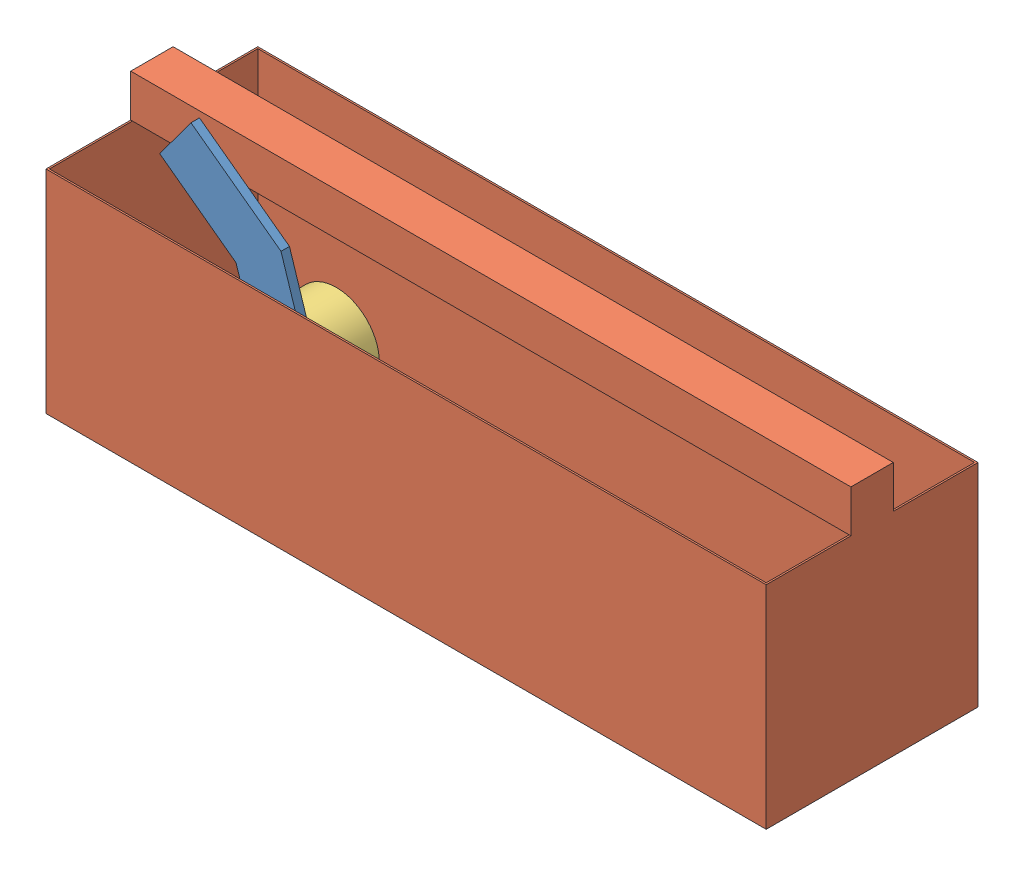
SolidWorks assembly mock_testrig, configuration Default. Lengths in mm.
Overall size (1700 600 500).
3 component instances, 3 part files, 3 mates.
Components (placement in the parent):
- temp_arm-1: temp_arm [Default] at (151.5439 88.2876 315.5893) size (371.14 459.34 20)
- temp_enclosure-1: temp_enclosure [Default] at (-232.0892 -108.995 15.5893) size (1700 600 500)
- temp_wheel-1: temp_wheel [Default] at (151.5439 88.2876 315.5893) x (0.997444 0.071447 0) z (0 0 1) size (203.2 203.2 101.6)
Mates (geometry in assembly coordinates):
- Concentric1: concentric anti-aligned: cylinder of temp_arm-1 through (151.5439 88.2876 335.5893) axis (0 0 -1) radius 16.1026; circle of temp_wheel-1
- Coincident1: coincident anti-aligned: plane of temp_arm-1 through (151.5439 88.2876 315.5893) normal (0 0 -1); plane of temp_wheel-1 through (151.5439 88.2876 315.5893) normal (0 0 1)
- Coincident2: coincident anti-aligned: plane of temp_arm-1 through (151.5439 88.2876 315.5893) normal (0 0 -1); plane of temp_enclosure-1 through (-373.5105 491.005 315.5893) normal (0 0 1)
